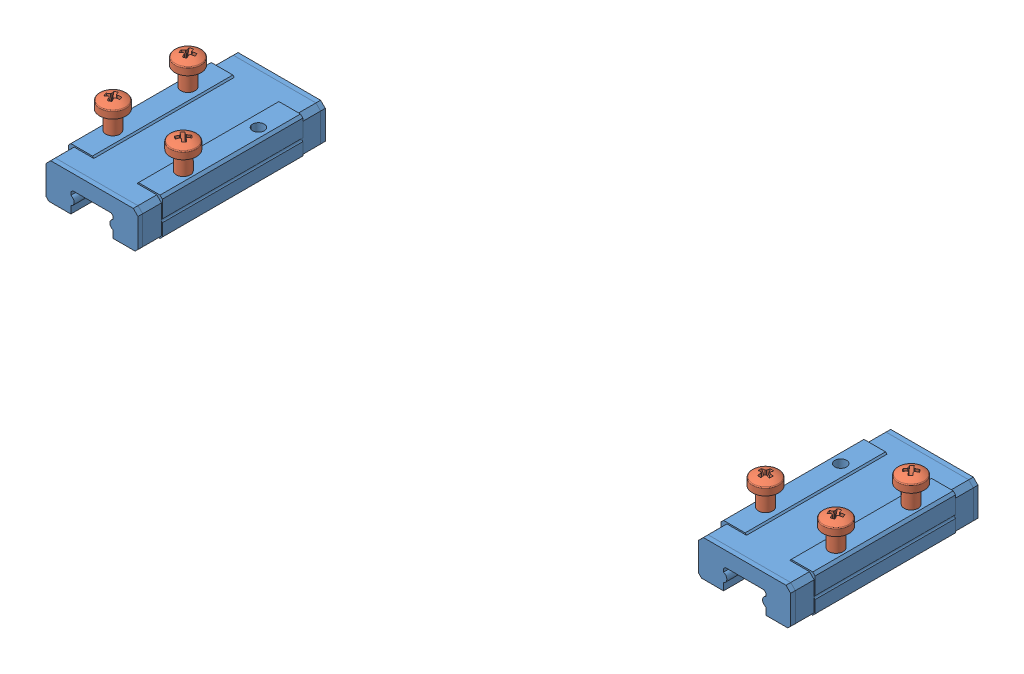
SolidWorks assembly Rail Assembly, configuration Default. Lengths in mm.
Overall size (161.6 14.41 39.97).
8 component instances, 2 part files, 4 mates.
Components (placement in the parent):
- Rail MGN9-1: Rail MGN9 [Default] at origin size (20 8.06 39.97)
- Rail MGN9-2: Rail MGN9 [Default] at (139 0 0) size (20 8.06 39.97)
- pan head cross recess screw_iso1-1: pan head cross recess screw_iso1 [ISO 7045 - M3 x 6 - Z --- 6N] at (7.5 9.9 8) x (0 -1 0) z (-0.780168 0 -0.62557) size (8.35 5.6 5.6)
- pan head cross recess screw_iso1-2: pan head cross recess screw_iso1 [ISO 7045 - M3 x 6 - Z --- 6N] at (-7.5 9.9 -8) x (0 -1 0) z (0.381849 0 0.924225) size (8.35 5.6 5.6)
- pan head cross recess screw_iso1-3: pan head cross recess screw_iso1 [ISO 7045 - M3 x 6 - Z --- 6N] at (146.5 9.9 8) x (0 -1 0) z (-0.364107 0 -0.931357) size (8.35 5.6 5.6)
- pan head cross recess screw_iso1-4: pan head cross recess screw_iso1 [ISO 7045 - M3 x 6 - Z --- 6N] at (131.5 9.9 8) x (0 -1 0) z (0.06083 0 -0.998148) size (8.35 5.6 5.6)
- pan head cross recess screw_iso1-5: pan head cross recess screw_iso1 [ISO 7045 - M3 x 6 - Z --- 6N] at (146.5 9.9 -8) x (0 -1 0) z (0.647519 0 0.762049) size (8.35 5.6 5.6)
- pan head cross recess screw_iso1-6: pan head cross recess screw_iso1 [ISO 7045 - M3 x 6 - Z --- 6N] at (-7.5 9.9 8) x (0 -1 0) z (0.381849 0 0.924225) size (8.35 5.6 5.6)
Mates (geometry in assembly coordinates):
- Concêntrico68: concentric anti-aligned: cylinder of pan head cross recess screw_iso-5 through (146.5 35.3 -8) axis (0 1 0) radius 1.5; cylinder of Rail MGN9-2 through (146.5 3.5 -8) axis (0 -1 0) radius 1.25
- Concêntrico75: concentric anti-aligned: cylinder of pan head cross recess screw_iso-4 through (131.5 35.3 8) axis (0 1 0) radius 1.5; cylinder of Rail MGN9-2 through (131.5 3.5 8) axis (0 -1 0) radius 1.25
- Concentric4005684: concentric anti-aligned: cylinder of pan head cross recess screw_iso-6 through (-7.5 35.3 8) axis (0 1 0) radius 1.5; cylinder of Rail MGN9-1 through (-7.5 3.5 8) axis (0 -1 0) radius 1.25
- Concentric4005685: concentric anti-aligned: cylinder of Rail MGN9-1 through (-7.5 3.5 8) axis (0 -1 0) radius 1.25; cylinder of pan head cross recess screw_iso-6 through (-7.5 35.3 8) axis (0 1 0) radius 1.5
